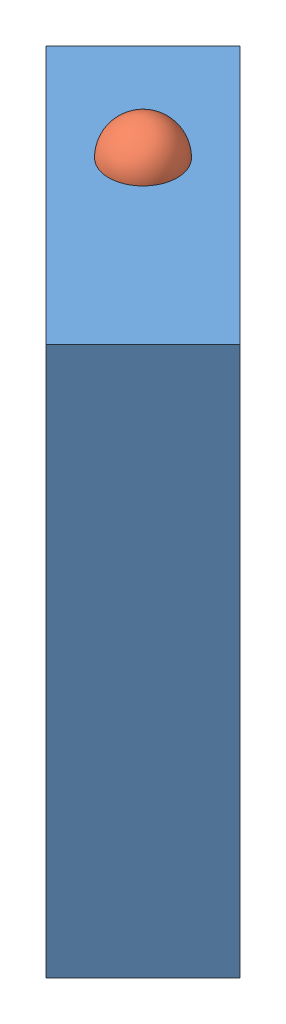
SolidWorks assembly load_cell, configuration Default. Lengths in mm.
Overall size (49.39 84.27 49.39).
2 component instances, 2 part files, 2 mates.
Components (placement in the parent):
- load_cell_2020-1: load_cell_2020 [Default] at (74.0871 9.525 87.5575) x (0.707107 0 -0.707107) z (0.707107 0 0.707107) size (19.05 76.2 50.8)
- load_cell_ball_bearing_2020-1: load_cell_ball_bearing_2020 [Default] at (58.3717 85.7631 58.3717) x (0.21646 -0.627281 -0.748107) z (0.752982 -0.380476 0.536896) size (9.53 9.53 9.53)
Mates (geometry in assembly coordinates):
- Concentric2: concentric: cylinder of load_cell_2020-1 through (58.3717 81.0006 58.3717) axis (0 1 0) radius 4.7244; sphere of load_cell_ball_bearing_2020-1
- Tangent6: tangent anti-aligned: plane of load_cell_2020-1 through (58.3717 81.0006 58.3717) normal (0 1 0); sphere of load_cell_ball_bearing_2020-1
